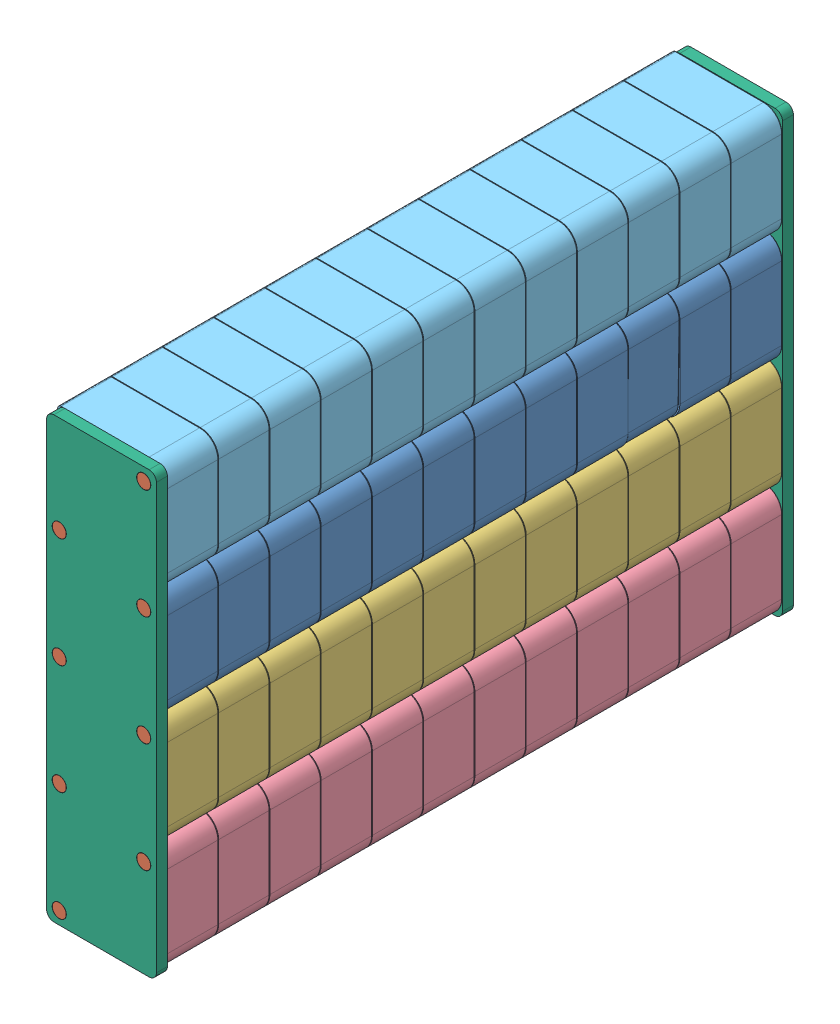
SolidWorks assembly SMD1, configuration Défaut. Lengths in mm.
Overall size (30.4 120 174).
58 component instances, 6 part files, 120 mates.
Components (placement in the parent):
- enrouleur3vert-1: enrouleur3vert [Défaut] at (-12.0195 14.474 22.9306) size (30 30 14.14)
- support-1: support [Défaut] at (14.5157 11.0092 5.9306) size (3.8 3.8 200)
- support-2: support [Défaut] at (-8.5588 -12.0653 5.9306) size (3.8 3.8 200)
- enrouleur3vert-2: enrouleur3vert [Défaut] at (-11.9707 14.8289 36.9306) x (0.99991 -0.013384 0) z (0 0 1) size (30 30 14.14)
- enrouleur3vert-3: enrouleur3vert [Défaut] at (-12.0195 14.474 50.9306) size (30 30 14.14)
- enrouleur-4: enrouleur [Défaut] at (-12.0195 -15.526 22.9306) size (30 30 14.14)
- enrouleur3vert-4: enrouleur3vert [Défaut] at (-12.0195 14.474 78.9306) size (30 30 14.14)
- enrouleur3vert-5: enrouleur3vert [Défaut] at (-12.0195 14.474 92.9306) size (30 30 14.14)
- enrouleur3vert-6: enrouleur3vert [Défaut] at (-12.0195 14.474 106.9306) size (30 30 14.14)
- enrouleur3vert-7: enrouleur3vert [Défaut] at (-12.0195 14.474 120.9306) size (30 30 14.14)
- enrouleur3vert-8: enrouleur3vert [Défaut] at (-12.0195 14.474 64.9306) size (30 30 14.14)
- enrouleur3vert-9: enrouleur3vert [Défaut] at (-12.0195 14.474 134.9306) size (30 30 14.14)
- enrouleur3vert-10: enrouleur3vert [Défaut] at (-12.0195 14.474 148.9306) size (30 30 14.14)
- enrouleur3vert-11: enrouleur3vert [Défaut] at (-12.0195 14.474 162.9306) size (30 30 14.14)
- support-3: support [Défaut] at (14.5157 -18.9908 5.9306) size (3.8 3.8 200)
- support-4: support [Défaut] at (-8.5588 -42.0653 5.9306) x (0.993936 -0.10996 0) z (0 0 1) size (3.8 3.8 200)
- enrouleur-5: enrouleur [Défaut] at (-12.0195 -15.526 78.9306) size (30 30 14.14)
- enrouleur-6: enrouleur [Défaut] at (-12.0195 -15.526 64.9306) size (30 30 14.14)
- enrouleur-7: enrouleur [Défaut] at (-12.0195 -15.526 92.9306) size (30 30 14.14)
- enrouleur-8: enrouleur [Défaut] at (-12.0195 -15.526 36.9306) size (30 30 14.14)
- enrouleur-9: enrouleur [Défaut] at (-12.0195 -15.526 50.9306) size (30 30 14.14)
- enrouleur-10: enrouleur [Défaut] at (-12.0195 -15.526 106.9306) size (30 30 14.14)
- enrouleur-11: enrouleur [Défaut] at (-12.0195 -15.526 120.9306) size (30 30 14.14)
- enrouleur-12: enrouleur [Défaut] at (-12.0195 -15.526 134.9306) size (30 30 14.14)
- enrouleur-13: enrouleur [Défaut] at (-12.0195 -15.526 148.9306) size (30 30 14.14)
- enrouleur-14: enrouleur [Défaut] at (-12.0195 -15.526 162.9306) size (30 30 14.14)
- enrouleur3violet-4: enrouleur3violet [Défaut] at (-12.0195 -45.526 22.9306) size (30 30 14.14)
- support-5: support [Défaut] at (14.5157 -48.9908 5.9306) size (3.8 3.8 200)
- support-6: support [Défaut] at (-8.5588 -72.0653 5.9306) size (3.8 3.8 200)
- enrouleur3violet-5: enrouleur3violet [Défaut] at (-12.0195 -45.526 36.9306) size (30 30 14.14)
- enrouleur3violet-6: enrouleur3violet [Défaut] at (-12.0195 -45.526 50.9306) size (30 30 14.14)
- enrouleur3violet-7: enrouleur3violet [Défaut] at (-12.0195 -45.526 64.9306) size (30 30 14.14)
- enrouleur3violet-8: enrouleur3violet [Défaut] at (-12.0195 -45.526 78.9306) size (30 30 14.14)
- enrouleur3violet-9: enrouleur3violet [Défaut] at (-12.0195 -45.526 92.9306) size (30 30 14.14)
- enrouleur3violet-10: enrouleur3violet [Défaut] at (-12.0195 -45.526 106.9306) size (30 30 14.14)
- enrouleur3violet-11: enrouleur3violet [Défaut] at (-12.0195 -45.526 120.9306) size (30 30 14.14)
- enrouleur3violet-12: enrouleur3violet [Défaut] at (-12.0195 -45.526 134.9306) size (30 30 14.14)
- enrouleur3violet-13: enrouleur3violet [Défaut] at (-12.0195 -45.526 148.9306) size (30 30 14.14)
- enrouleur3violet-14: enrouleur3violet [Défaut] at (-12.0195 -45.526 162.9306) size (30 30 14.14)
- enrouleur2rouge-15: enrouleur2rouge [Défaut] at (-12.0195 44.474 22.9306) size (30 30 14.14)
- support-7: support [Défaut] at (14.5157 41.0092 5.9306) size (3.8 3.8 200)
- support-8: support [Défaut] at (-8.5588 17.9347 5.9306) size (3.8 3.8 200)
- enrouleur2rouge-16: enrouleur2rouge [Défaut] at (-12.0195 44.474 36.9306) size (30 30 14.14)
- enrouleur2rouge-17: enrouleur2rouge [Défaut] at (-12.0195 44.474 50.9306) size (30 30 14.14)
- enrouleur2rouge-18: enrouleur2rouge [Défaut] at (-12.0195 44.474 64.9306) size (30 30 14.14)
- enrouleur2rouge-19: enrouleur2rouge [Défaut] at (-12.0195 44.474 78.9306) size (30 30 14.14)
- enrouleur2rouge-20: enrouleur2rouge [Défaut] at (-12.0195 44.474 92.9306) size (30 30 14.14)
- enrouleur2rouge-21: enrouleur2rouge [Défaut] at (-12.0195 44.474 106.9306) size (30 30 14.14)
- enrouleur2rouge-22: enrouleur2rouge [Défaut] at (-12.0195 44.474 120.9306) size (30 30 14.14)
- enrouleur2rouge-23: enrouleur2rouge [Défaut] at (-12.0195 44.474 134.9306) size (30 30 14.14)
- enrouleur2rouge-24: enrouleur2rouge [Défaut] at (-12.0195 44.474 148.9306) size (30 30 14.14)
- enrouleur2rouge-25: enrouleur2rouge [Défaut] at (-12.0195 44.474 162.9306) size (30 30 14.14)
- enrouleur2rouge-26: enrouleur2rouge [Défaut] at (-12.0195 44.474 8.9306) size (30 30 14.14)
- enrouleur3vert-12: enrouleur3vert [Défaut] at (-12.0195 14.474 8.9306) size (30 30 14.14)
- enrouleur-15: enrouleur [Défaut] at (-12.0195 -15.526 8.9306) size (30 30 14.14)
- enrouleur3violet-15: enrouleur3violet [Défaut] at (-12.0195 -45.526 8.9306) size (30 30 14.14)
- facades-1: facades [Défaut] at (-12.0195 -75.526 176.9306) size (30 120 3)
- facades-2: facades [Défaut] at (-12.0195 -75.526 5.9306) size (30 120 3)
Mates (geometry in assembly coordinates):
- Coaxiale1: concentric anti-aligned: cylinder of enrouleur-1 through (14.5157 11.0092 22.9306) axis (0 0 1) radius 2; cylinder of support-1 through (14.5157 11.0092 205.9306) axis (0 0 -1) radius 1.9
- Coaxiale2: concentric anti-aligned: cylinder of enrouleur-1 through (-8.5588 -12.0653 22.9306) axis (0 0 1) radius 2; cylinder of support-2 through (-8.5588 -12.0653 205.9306) axis (0 0 -1) radius 1.9
- Coïncidente1: coincident aligned: plane of support-1 through (14.5157 11.0092 5.9306) normal (0 0 -1); plane of support-2 through (-8.5588 -12.0653 5.9306) normal (0 0 -1)
- Coaxiale3: concentric anti-aligned: cylinder of support-1 through (14.5157 11.0092 205.9306) axis (0 0 -1) radius 1.9; cylinder of enrouleur-2 through (14.5157 11.0092 36.9306) axis (0 0 1) radius 2
- Coaxiale4: concentric anti-aligned: cylinder of support-2 through (-8.5588 -12.0653 205.9306) axis (0 0 -1) radius 1.9; cylinder of enrouleur-3 through (-8.5588 -12.0653 50.9306) axis (0 0 1) radius 2
- Coaxiale5: concentric anti-aligned: cylinder of support-1 through (14.5157 11.0092 205.9306) axis (0 0 -1) radius 1.9; cylinder of enrouleur-3 through (14.5157 11.0092 50.9306) axis (0 0 1) radius 2
- Coïncidente3: coincident anti-aligned: plane of enrouleur3vert-1 through (-7.0195 -10.526 36.9306) normal (0 0 1); plane of enrouleur3vert-2 through (-7.3058 -10.2358 36.9306) normal (0 0 -1)
- Coïncidente4: coincident anti-aligned: plane of enrouleur3vert-2 through (-7.3058 -10.2358 50.9306) normal (0 0 1); plane of enrouleur3vert-3 through (-7.0195 -10.526 50.9306) normal (0 0 -1)
- Coaxiale6: concentric anti-aligned: cylinder of support-1 through (14.5157 11.0092 205.9306) axis (0 0 -1) radius 1.9; cylinder of enrouleur3vert-8 through (14.5157 11.0092 64.9306) axis (0 0 1) radius 2
- Coaxiale7: concentric anti-aligned: cylinder of support-1 through (14.5157 11.0092 205.9306) axis (0 0 -1) radius 1.9; cylinder of enrouleur3vert-4 through (14.5157 11.0092 78.9306) axis (0 0 1) radius 2
- Coaxiale8: concentric anti-aligned: cylinder of support-1 through (14.5157 11.0092 205.9306) axis (0 0 -1) radius 1.9; cylinder of enrouleur3vert-5 through (14.5157 11.0092 92.9306) axis (0 0 1) radius 2
- Coaxiale9: concentric anti-aligned: cylinder of support-1 through (14.5157 11.0092 205.9306) axis (0 0 -1) radius 1.9; cylinder of enrouleur3vert-6 through (14.5157 11.0092 106.9306) axis (0 0 1) radius 2
- Coaxiale10: concentric anti-aligned: cylinder of support-1 through (14.5157 11.0092 205.9306) axis (0 0 -1) radius 1.9; cylinder of enrouleur3vert-7 through (14.5157 11.0092 120.9306) axis (0 0 1) radius 2
- Coïncidente5: coincident anti-aligned: plane of enrouleur3vert-3 through (-7.0195 -10.526 64.9306) normal (0 0 1); plane of enrouleur3vert-8 through (-7.0195 -10.526 64.9306) normal (0 0 -1)
- Coïncidente6: coincident anti-aligned: plane of enrouleur3vert-4 through (-7.0195 -10.526 78.9306) normal (0 0 -1); plane of enrouleur3vert-8 through (-7.0195 -10.526 78.9306) normal (0 0 1)
- Coïncidente7: coincident anti-aligned: plane of enrouleur3vert-4 through (-7.0195 -10.526 92.9306) normal (0 0 1); plane of enrouleur3vert-5 through (-7.0195 -10.526 92.9306) normal (0 0 -1)
- Coïncidente8: coincident anti-aligned: plane of enrouleur3vert-5 through (-7.0195 -10.526 106.9306) normal (0 0 1); plane of enrouleur3vert-6 through (-7.0195 -10.526 106.9306) normal (0 0 -1)
- Coïncidente9: coincident anti-aligned: plane of enrouleur3vert-6 through (-7.0195 -10.526 120.9306) normal (0 0 1); plane of enrouleur3vert-7 through (-7.0195 -10.526 120.9306) normal (0 0 -1)
- Coaxiale11: concentric anti-aligned: cylinder of support-1 through (14.5157 11.0092 205.9306) axis (0 0 -1) radius 1.9; cylinder of enrouleur3vert-9 through (14.5157 11.0092 134.9306) axis (0 0 1) radius 2
- Coaxiale12: concentric anti-aligned: cylinder of support-1 through (14.5157 11.0092 205.9306) axis (0 0 -1) radius 1.9; cylinder of enrouleur3vert-10 through (14.5157 11.0092 148.9306) axis (0 0 1) radius 2
- Coaxiale13: concentric anti-aligned: cylinder of support-1 through (14.5157 11.0092 205.9306) axis (0 0 -1) radius 1.9; cylinder of enrouleur3vert-11 through (14.5157 11.0092 162.9306) axis (0 0 1) radius 2
- Coïncidente10: coincident anti-aligned: plane of enrouleur3vert-7 through (-7.0195 -10.526 134.9306) normal (0 0 1); plane of enrouleur3vert-9 through (-7.0195 -10.526 134.9306) normal (0 0 -1)
- Coïncidente11: coincident anti-aligned: plane of enrouleur3vert-9 through (-7.0195 -10.526 148.9306) normal (0 0 1); plane of enrouleur3vert-10 through (-7.0195 -10.526 148.9306) normal (0 0 -1)
- Coïncidente12: coincident anti-aligned: plane of enrouleur3vert-10 through (-7.0195 -10.526 162.9306) normal (0 0 1); plane of enrouleur3vert-11 through (-7.0195 -10.526 162.9306) normal (0 0 -1)
- Coïncidente13: coincident anti-aligned: plane of enrouleur3vert-1 through (-7.0195 -15.526 36.9306) normal (0 -1 0); plane of enrouleur-4 through (-12.0195 -15.526 36.9306) normal (0 1 0)
- Coïncidente14: coincident aligned: plane of enrouleur3vert-1 through (17.9805 9.474 36.9306) normal (1 0 0); plane of enrouleur-4 through (17.9805 -20.526 36.9306) normal (1 0 0)
- Coïncidente15: coincident aligned: plane of enrouleur3vert-1 through (-7.0195 -10.526 22.9306) normal (0 0 -1); plane of enrouleur-4 through (-7.0195 -40.526 22.9306) normal (0 0 -1)
- Coaxiale14: concentric anti-aligned: cylinder of enrouleur-4 through (14.5157 -18.9908 22.9306) axis (0 0 1) radius 2; cylinder of support-3 through (14.5157 -18.9908 205.9306) axis (0 0 -1) radius 1.9
- Parallèle1: parallel aligned: plane of support-1 through (14.5157 11.0092 5.9306) normal (0 0 -1); plane of support-3 through (14.5157 -18.9908 5.9306) normal (0 0 -1)
- Coaxiale15: concentric anti-aligned: cylinder of enrouleur-4 through (-8.5588 -42.0653 22.9306) axis (0 0 1) radius 2; cylinder of support-4 through (-8.5588 -42.0653 205.9306) axis (0 0 -1) radius 1.9
- Coaxiale16: concentric anti-aligned: cylinder of support-3 through (14.5157 -18.9908 205.9306) axis (0 0 -1) radius 1.9; cylinder of enrouleur-8 through (14.5157 -18.9908 36.9306) axis (0 0 1) radius 2
- Coaxiale17: concentric anti-aligned: cylinder of support-4 through (-8.5588 -42.0653 205.9306) axis (0 0 -1) radius 1.9; cylinder of enrouleur-8 through (-8.5588 -42.0653 36.9306) axis (0 0 1) radius 2
- Coïncidente17: coincident anti-aligned: plane of enrouleur-4 through (-7.0195 -40.526 36.9306) normal (0 0 1); plane of enrouleur-8 through (-7.0195 -40.526 36.9306) normal (0 0 -1)
- Coïncidente18: coincident aligned: cylinder of enrouleur-10 through (14.5157 -18.9908 106.9306) axis (0 0 1) radius 2; circle of enrouleur-11
- Coaxiale19: concentric aligned: cylinder of enrouleur-7 through (14.5157 -18.9908 92.9306) axis (0 0 1) radius 2; cylinder of enrouleur-10 through (14.5157 -18.9908 106.9306) axis (0 0 1) radius 2
- Coaxiale20: concentric aligned: cylinder of enrouleur-5 through (14.5157 -18.9908 78.9306) axis (0 0 1) radius 2; cylinder of enrouleur-7 through (14.5157 -18.9908 92.9306) axis (0 0 1) radius 2
- Coaxiale21: concentric aligned: cylinder of enrouleur-5 through (14.5157 -18.9908 78.9306) axis (0 0 1) radius 2; cylinder of enrouleur-6 through (14.5157 -18.9908 64.9306) axis (0 0 1) radius 2
- Coaxiale22: concentric aligned: cylinder of enrouleur-6 through (14.5157 -18.9908 64.9306) axis (0 0 1) radius 2; cylinder of enrouleur-9 through (14.5157 -18.9908 50.9306) axis (0 0 1) radius 2
- Coaxiale23: concentric anti-aligned: cylinder of support-3 through (14.5157 -18.9908 205.9306) axis (0 0 -1) radius 1.9; cylinder of enrouleur-9 through (14.5157 -18.9908 50.9306) axis (0 0 1) radius 2
- Coïncidente20: coincident anti-aligned: plane of enrouleur-8 through (-7.0195 -40.526 50.9306) normal (0 0 1); plane of enrouleur-9 through (-7.0195 -40.526 50.9306) normal (0 0 -1)
- Coïncidente21: coincident anti-aligned: plane of enrouleur-6 through (-7.0195 -40.526 64.9306) normal (0 0 -1); plane of enrouleur-9 through (-7.0195 -40.526 64.9306) normal (0 0 1)
- Coïncidente23: coincident anti-aligned: plane of enrouleur-5 through (-7.0195 -40.526 78.9306) normal (0 0 -1); plane of enrouleur-6 through (-7.0195 -40.526 78.9306) normal (0 0 1)
- Coïncidente24: coincident anti-aligned: plane of enrouleur-5 through (-7.0195 -40.526 92.9306) normal (0 0 1); plane of enrouleur-7 through (-7.0195 -40.526 92.9306) normal (0 0 -1)
- Coïncidente25: coincident anti-aligned: plane of enrouleur-7 through (-7.0195 -40.526 106.9306) normal (0 0 1); plane of enrouleur-10 through (-7.0195 -40.526 106.9306) normal (0 0 -1)
- Coïncidente26: coincident anti-aligned: plane of enrouleur-10 through (-7.0195 -40.526 120.9306) normal (0 0 1); plane of enrouleur-11 through (-7.0195 -40.526 120.9306) normal (0 0 -1)
- Coaxiale24: concentric anti-aligned: cylinder of support-3 through (14.5157 -18.9908 205.9306) axis (0 0 -1) radius 1.9; cylinder of enrouleur-12 through (14.5157 -18.9908 134.9306) axis (0 0 1) radius 2
- Coaxiale25: concentric anti-aligned: cylinder of support-3 through (14.5157 -18.9908 205.9306) axis (0 0 -1) radius 1.9; cylinder of enrouleur-13 through (14.5157 -18.9908 148.9306) axis (0 0 1) radius 2
- Coïncidente27: coincident anti-aligned: plane of enrouleur-11 through (-7.0195 -40.526 134.9306) normal (0 0 1); plane of enrouleur-12 through (-7.0195 -40.526 134.9306) normal (0 0 -1)
- Coïncidente28: coincident anti-aligned: plane of enrouleur-12 through (-7.0195 -40.526 148.9306) normal (0 0 1); plane of enrouleur-13 through (-7.0195 -40.526 148.9306) normal (0 0 -1)
- Coaxiale27: concentric anti-aligned: cylinder of support-3 through (14.5157 -18.9908 205.9306) axis (0 0 -1) radius 1.9; cylinder of enrouleur-14 through (14.5157 -18.9908 162.9306) axis (0 0 1) radius 2
- Coïncidente29: coincident anti-aligned: plane of enrouleur-13 through (-7.0195 -40.526 162.9306) normal (0 0 1); plane of enrouleur-14 through (-7.0195 -40.526 162.9306) normal (0 0 -1)
- Coïncidente30: coincident anti-aligned: plane of enrouleur-4 through (-7.0195 -45.526 36.9306) normal (0 -1 0); plane of enrouleur2rouge-4 through (-12.0195 -45.526 36.9306) normal (0 1 0)
- Coïncidente31: coincident aligned: plane of enrouleur-4 through (17.9805 -20.526 36.9306) normal (1 0 0); plane of enrouleur2rouge-4 through (17.9805 -50.526 36.9306) normal (1 0 0)
- Coïncidente32: coincident aligned: plane of enrouleur-4 through (-7.0195 -40.526 22.9306) normal (0 0 -1); plane of enrouleur2rouge-4 through (-7.0195 -70.526 22.9306) normal (0 0 -1)
- Coïncidente35: coincident anti-aligned: circle of support-3; plane of support-5 through (14.5157 -48.9908 5.9306) normal (0 0 -1)
- Coaxiale29: concentric anti-aligned: cylinder of enrouleur2rouge-4 through (14.5157 -48.9908 22.9306) axis (0 0 1) radius 2; cylinder of support-5 through (14.5157 -48.9908 205.9306) axis (0 0 -1) radius 1.9
- Coïncidente36: coincident aligned: plane of support-5 through (14.5157 -48.9908 5.9306) normal (0 0 -1); plane of support-6 through (-8.5588 -72.0653 5.9306) normal (0 0 -1)
- Coaxiale34: concentric anti-aligned: cylinder of enrouleur2rouge-4 through (-8.5588 -72.0653 22.9306) axis (0 0 1) radius 2; cylinder of support-6 through (-8.5588 -72.0653 205.9306) axis (0 0 -1) radius 1.9
- Coaxiale35: concentric aligned: cylinder of support-6 through (-8.5588 -72.0653 205.9306) axis (0 0 -1) radius 1.9; circle of enrouleur2rouge-5
- Coïncidente37: coincident anti-aligned: plane of enrouleur2rouge-4 through (-7.0195 -70.526 36.9306) normal (0 0 1); plane of enrouleur2rouge-5 through (-7.0195 -70.526 36.9306) normal (0 0 -1)
- Coaxiale36: concentric anti-aligned: cylinder of support-5 through (14.5157 -48.9908 205.9306) axis (0 0 -1) radius 1.9; cylinder of enrouleur2rouge-6 through (14.5157 -48.9908 50.9306) axis (0 0 1) radius 2
- Coïncidente38: coincident anti-aligned: plane of enrouleur2rouge-5 through (-7.0195 -70.526 50.9306) normal (0 0 1); plane of enrouleur2rouge-6 through (-7.0195 -70.526 50.9306) normal (0 0 -1)
- Coaxiale37: concentric anti-aligned: cylinder of support-5 through (14.5157 -48.9908 205.9306) axis (0 0 -1) radius 1.9; cylinder of enrouleur2rouge-7 through (14.5157 -48.9908 64.9306) axis (0 0 1) radius 2
- Coaxiale38: concentric anti-aligned: cylinder of support-5 through (14.5157 -48.9908 205.9306) axis (0 0 -1) radius 1.9; cylinder of enrouleur2rouge-8 through (14.5157 -48.9908 78.9306) axis (0 0 1) radius 2
- Coïncidente39: coincident anti-aligned: plane of enrouleur2rouge-6 through (-7.0195 -70.526 64.9306) normal (0 0 1); plane of enrouleur2rouge-7 through (-7.0195 -70.526 64.9306) normal (0 0 -1)
- Coïncidente40: coincident anti-aligned: plane of enrouleur2rouge-7 through (-7.0195 -70.526 78.9306) normal (0 0 1); plane of enrouleur2rouge-8 through (-7.0195 -70.526 78.9306) normal (0 0 -1)
- Coaxiale39: concentric anti-aligned: cylinder of support-5 through (14.5157 -48.9908 205.9306) axis (0 0 -1) radius 1.9; cylinder of enrouleur2rouge-9 through (14.5157 -48.9908 92.9306) axis (0 0 1) radius 2
- Coïncidente41: coincident anti-aligned: plane of enrouleur2rouge-8 through (-7.0195 -70.526 92.9306) normal (0 0 1); plane of enrouleur2rouge-9 through (-7.0195 -70.526 92.9306) normal (0 0 -1)
- Coaxiale40: concentric anti-aligned: cylinder of support-5 through (14.5157 -48.9908 205.9306) axis (0 0 -1) radius 1.9; cylinder of enrouleur2rouge-10 through (14.5157 -48.9908 106.9306) axis (0 0 1) radius 2
- Coïncidente42: coincident anti-aligned: plane of enrouleur2rouge-9 through (-7.0195 -70.526 106.9306) normal (0 0 1); plane of enrouleur2rouge-10 through (-7.0195 -70.526 106.9306) normal (0 0 -1)
- Coaxiale41: concentric anti-aligned: cylinder of support-5 through (14.5157 -48.9908 205.9306) axis (0 0 -1) radius 1.9; cylinder of enrouleur2rouge-11 through (14.5157 -48.9908 120.9306) axis (0 0 1) radius 2
- Coïncidente43: coincident anti-aligned: plane of enrouleur2rouge-10 through (-7.0195 -70.526 120.9306) normal (0 0 1); plane of enrouleur2rouge-11 through (-7.0195 -70.526 120.9306) normal (0 0 -1)
- Coaxiale42: concentric anti-aligned: cylinder of support-5 through (14.5157 -48.9908 205.9306) axis (0 0 -1) radius 1.9; cylinder of enrouleur2rouge-12 through (14.5157 -48.9908 134.9306) axis (0 0 1) radius 2
- Coïncidente44: coincident anti-aligned: plane of enrouleur2rouge-11 through (-7.0195 -70.526 134.9306) normal (0 0 1); plane of enrouleur2rouge-12 through (-7.0195 -70.526 134.9306) normal (0 0 -1)
- Coaxiale43: concentric anti-aligned: cylinder of support-5 through (14.5157 -48.9908 205.9306) axis (0 0 -1) radius 1.9; cylinder of enrouleur2rouge-13 through (14.5157 -48.9908 148.9306) axis (0 0 1) radius 2
- Coïncidente45: coincident anti-aligned: plane of enrouleur2rouge-12 through (-7.0195 -70.526 148.9306) normal (0 0 1); plane of enrouleur2rouge-13 through (-7.0195 -70.526 148.9306) normal (0 0 -1)
- Coaxiale44: concentric anti-aligned: cylinder of support-5 through (14.5157 -48.9908 205.9306) axis (0 0 -1) radius 1.9; cylinder of enrouleur2rouge-14 through (14.5157 -48.9908 162.9306) axis (0 0 1) radius 2
- Coïncidente46: coincident anti-aligned: plane of enrouleur2rouge-13 through (-7.0195 -70.526 162.9306) normal (0 0 1); plane of enrouleur2rouge-14 through (-7.0195 -70.526 162.9306) normal (0 0 -1)
- Coïncidente47: coincident anti-aligned: plane of enrouleur3vert-1 through (-12.0195 14.474 36.9306) normal (0 1 0); plane of enrouleur2rouge-15 through (-7.0195 14.474 36.9306) normal (0 -1 0)
- Coïncidente48: coincident aligned: plane of enrouleur3vert-1 through (-12.0195 14.474 36.9306) normal (-1 0 0); plane of enrouleur2rouge-15 through (-12.0195 44.474 36.9306) normal (-1 0 0)
- Coïncidente49: coincident aligned: plane of enrouleur3vert-1 through (-7.0195 -10.526 22.9306) normal (0 0 -1); plane of enrouleur2rouge-15 through (-7.0195 19.474 22.9306) normal (0 0 -1)
- Coïncidente50: coincident anti-aligned: circle of support-1; plane of support-7 through (14.5157 41.0092 5.9306) normal (0 0 -1)
- Coaxiale45: concentric anti-aligned: cylinder of enrouleur2rouge-15 through (14.5157 41.0092 22.9306) axis (0 0 1) radius 2; cylinder of support-7 through (14.5157 41.0092 205.9306) axis (0 0 -1) radius 1.9
- Coïncidente51: coincident anti-aligned: circle of support-7; plane of support-8 through (-8.5588 17.9347 5.9306) normal (0 0 -1)
- Coaxiale46: concentric anti-aligned: cylinder of enrouleur2rouge-15 through (-8.5588 17.9347 22.9306) axis (0 0 1) radius 2; cylinder of support-8 through (-8.5588 17.9347 205.9306) axis (0 0 -1) radius 1.9
- Coaxiale47: concentric anti-aligned: cylinder of support-7 through (14.5157 41.0092 205.9306) axis (0 0 -1) radius 1.9; cylinder of enrouleur2rouge-16 through (14.5157 41.0092 36.9306) axis (0 0 1) radius 2
- Coïncidente52: coincident anti-aligned: plane of enrouleur2rouge-15 through (-7.0195 19.474 36.9306) normal (0 0 1); plane of enrouleur2rouge-16 through (-7.0195 19.474 36.9306) normal (0 0 -1)
- Coaxiale49: concentric anti-aligned: cylinder of support-7 through (14.5157 41.0092 205.9306) axis (0 0 -1) radius 1.9; cylinder of enrouleur2rouge-17 through (14.5157 41.0092 50.9306) axis (0 0 1) radius 2
- Coïncidente53: coincident anti-aligned: plane of enrouleur2rouge-16 through (-7.0195 19.474 50.9306) normal (0 0 1); plane of enrouleur2rouge-17 through (-7.0195 19.474 50.9306) normal (0 0 -1)
- Coaxiale50: concentric anti-aligned: cylinder of support-7 through (14.5157 41.0092 205.9306) axis (0 0 -1) radius 1.9; cylinder of enrouleur2rouge-18 through (14.5157 41.0092 64.9306) axis (0 0 1) radius 2
- Coïncidente54: coincident anti-aligned: plane of enrouleur2rouge-17 through (-7.0195 19.474 64.9306) normal (0 0 1); plane of enrouleur2rouge-18 through (-7.0195 19.474 64.9306) normal (0 0 -1)
- Coaxiale51: concentric anti-aligned: cylinder of support-7 through (14.5157 41.0092 205.9306) axis (0 0 -1) radius 1.9; cylinder of enrouleur2rouge-19 through (14.5157 41.0092 78.9306) axis (0 0 1) radius 2
- Coïncidente56: coincident anti-aligned: plane of enrouleur2rouge-18 through (-7.0195 19.474 78.9306) normal (0 0 1); plane of enrouleur2rouge-19 through (-7.0195 19.474 78.9306) normal (0 0 -1)
- Coaxiale52: concentric anti-aligned: cylinder of support-7 through (14.5157 41.0092 205.9306) axis (0 0 -1) radius 1.9; cylinder of enrouleur2rouge-20 through (14.5157 41.0092 92.9306) axis (0 0 1) radius 2
- Coïncidente57: coincident anti-aligned: plane of enrouleur2rouge-19 through (-7.0195 19.474 92.9306) normal (0 0 1); plane of enrouleur2rouge-20 through (-7.0195 19.474 92.9306) normal (0 0 -1)
- Coaxiale53: concentric anti-aligned: cylinder of support-7 through (14.5157 41.0092 205.9306) axis (0 0 -1) radius 1.9; cylinder of enrouleur2rouge-21 through (14.5157 41.0092 106.9306) axis (0 0 1) radius 2
- Coïncidente58: coincident anti-aligned: plane of enrouleur2rouge-20 through (-7.0195 19.474 106.9306) normal (0 0 1); plane of enrouleur2rouge-21 through (-7.0195 19.474 106.9306) normal (0 0 -1)
- Coaxiale54: concentric anti-aligned: cylinder of support-7 through (14.5157 41.0092 205.9306) axis (0 0 -1) radius 1.9; cylinder of enrouleur2rouge-22 through (14.5157 41.0092 120.9306) axis (0 0 1) radius 2
- Coïncidente59: coincident anti-aligned: plane of enrouleur2rouge-21 through (-7.0195 19.474 120.9306) normal (0 0 1); plane of enrouleur2rouge-22 through (-7.0195 19.474 120.9306) normal (0 0 -1)
- Coaxiale55: concentric anti-aligned: cylinder of support-7 through (14.5157 41.0092 205.9306) axis (0 0 -1) radius 1.9; cylinder of enrouleur2rouge-23 through (14.5157 41.0092 134.9306) axis (0 0 1) radius 2
- Coïncidente60: coincident anti-aligned: plane of enrouleur2rouge-22 through (-7.0195 19.474 134.9306) normal (0 0 1); plane of enrouleur2rouge-23 through (-7.0195 19.474 134.9306) normal (0 0 -1)
- Coaxiale56: concentric anti-aligned: cylinder of support-7 through (14.5157 41.0092 205.9306) axis (0 0 -1) radius 1.9; cylinder of enrouleur2rouge-24 through (14.5157 41.0092 148.9306) axis (0 0 1) radius 2
- Coïncidente61: coincident anti-aligned: plane of enrouleur2rouge-23 through (-7.0195 19.474 148.9306) normal (0 0 1); plane of enrouleur2rouge-24 through (-7.0195 19.474 148.9306) normal (0 0 -1)
- Coaxiale57: concentric anti-aligned: cylinder of support-7 through (14.5157 41.0092 205.9306) axis (0 0 -1) radius 1.9; cylinder of enrouleur2rouge-25 through (14.5157 41.0092 162.9306) axis (0 0 1) radius 2
- Coïncidente62: coincident anti-aligned: plane of enrouleur2rouge-24 through (-7.0195 19.474 162.9306) normal (0 0 1); plane of enrouleur2rouge-25 through (-7.0195 19.474 162.9306) normal (0 0 -1)
- Coaxiale58: concentric anti-aligned: cylinder of support-7 through (14.5157 41.0092 205.9306) axis (0 0 -1) radius 1.9; cylinder of enrouleur2rouge-26 through (14.5157 41.0092 8.9306) axis (0 0 1) radius 2
- Coïncidente63: coincident anti-aligned: plane of enrouleur2rouge-15 through (-7.0195 19.474 22.9306) normal (0 0 -1); plane of enrouleur2rouge-26 through (-7.0195 19.474 22.9306) normal (0 0 1)
- Coaxiale59: concentric anti-aligned: cylinder of support-1 through (14.5157 11.0092 205.9306) axis (0 0 -1) radius 1.9; cylinder of enrouleur3vert-12 through (14.5157 11.0092 8.9306) axis (0 0 1) radius 2
- Coïncidente64: coincident anti-aligned: plane of enrouleur3vert-1 through (-7.0195 -10.526 22.9306) normal (0 0 -1); plane of enrouleur3vert-12 through (-7.0195 -10.526 22.9306) normal (0 0 1)
- Coaxiale60: concentric anti-aligned: cylinder of support-3 through (14.5157 -18.9908 205.9306) axis (0 0 -1) radius 1.9; cylinder of enrouleur-15 through (14.5157 -18.9908 8.9306) axis (0 0 1) radius 2
- Coïncidente65: coincident anti-aligned: plane of enrouleur-4 through (-7.0195 -40.526 22.9306) normal (0 0 -1); plane of enrouleur-15 through (-7.0195 -40.526 22.9306) normal (0 0 1)
- Coaxiale61: concentric anti-aligned: cylinder of support-5 through (14.5157 -48.9908 205.9306) axis (0 0 -1) radius 1.9; cylinder of enrouleur3violet-15 through (14.5157 -48.9908 8.9306) axis (0 0 1) radius 2
- Coïncidente66: coincident anti-aligned: plane of enrouleur3violet-4 through (-7.0195 -70.526 22.9306) normal (0 0 -1); plane of enrouleur3violet-15 through (-7.0195 -70.526 22.9306) normal (0 0 1)
- Parallèle4: parallel aligned: plane of enrouleur2rouge-26 through (-12.0195 44.474 22.9306) normal (-1 0 0); plane of facades-2 through (-12.0195 -73.526 8.9306) normal (-1 0 0)
- Coïncidente72: coincident aligned: plane of enrouleur2rouge-26 through (-12.0195 44.474 22.9306) normal (0 1 0); plane of facades-2 through (-10.0195 44.474 8.9306) normal (0 1 0)
- Coïncidente73: coincident anti-aligned: plane of enrouleur2rouge-26 through (-7.0195 19.474 8.9306) normal (0 0 -1); plane of facades-2 through (-10.0195 -73.526 8.9306) normal (0 0 1)
- Coïncidente74: coincident aligned: plane of facades-2 through (-12.0195 -73.526 8.9306) normal (-1 0 0)
- Coïncidente76: coincident anti-aligned: circle of support-7; plane of facades-2 through (-10.0195 -73.526 5.9306) normal (0 0 -1)
- Coïncidente77: coincident anti-aligned: circle of support-3; plane of facades-2 through (-10.0195 -73.526 5.9306) normal (0 0 -1)
- Coïncidente79: coincident anti-aligned: circle of support-4; plane of facades-2 through (-10.0195 -73.526 5.9306) normal (0 0 -1)
